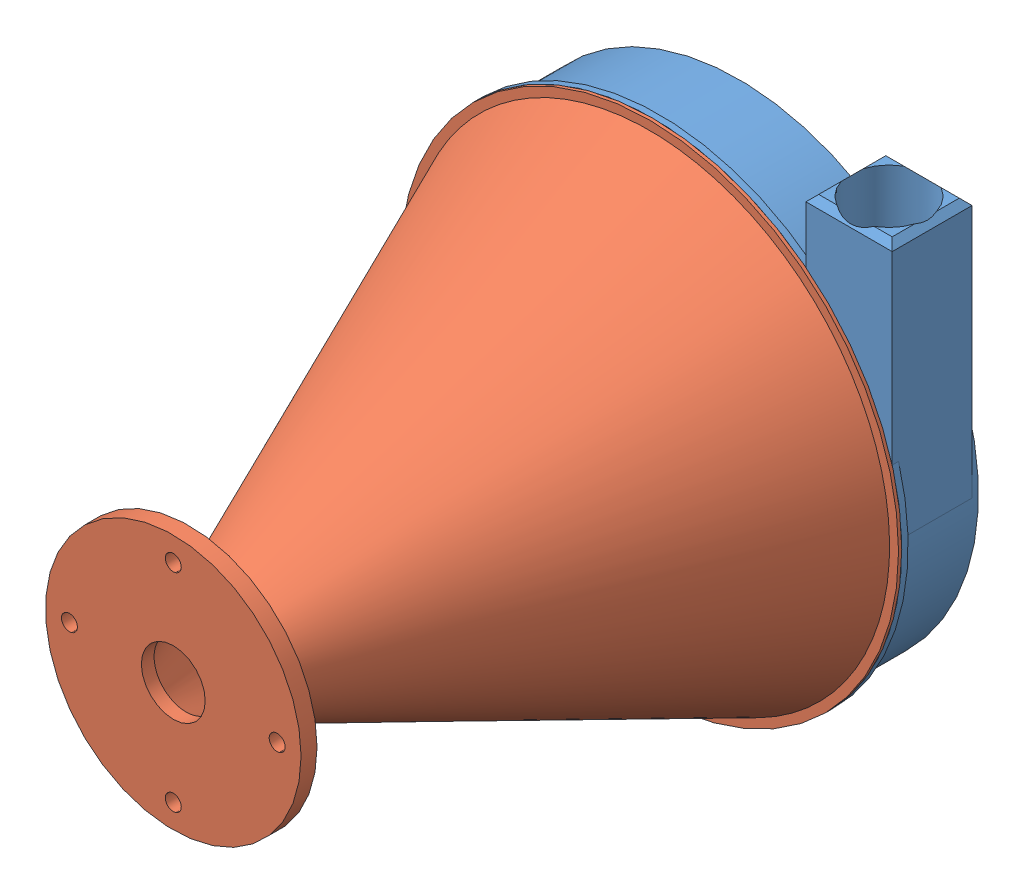
SolidWorks assembly montagem, configuration Default. Lengths in mm.
Overall size (162.46 160.09 177).
2 component instances, 2 part files, 2 mates.
Components (placement in the parent):
- tampa-1: tampa [Default] at (26.6103 106.1585 123.9507) size (156 159.29 52)
- cone-3: cone [Default] at (26.6103 106.1585 148.9507) size (162.46 157.61 150)
Mates (geometry in assembly coordinates):
- Coincident5: coincident: plane of tampa-1 through (26.6103 106.1585 148.9507) normal (0 0 1); plane of cone-3 through (-87.0539 239.2043 148.9507) normal (0 0 -1)
- Concentric2: concentric anti-aligned: cylinder of tampa-1 through (26.6103 106.1585 148.9507) axis (0 0 -1) radius 73; circle of cone-3
